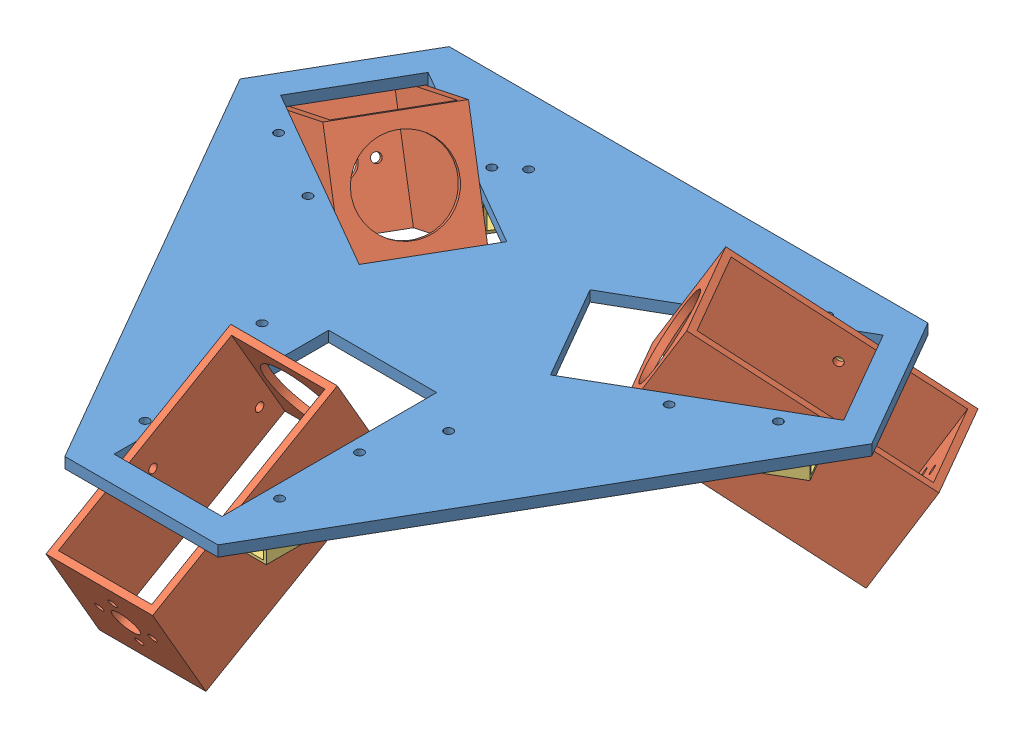
SolidWorks assembly 玉乗りロボット, configuration ﾃﾞﾌｫﾙﾄ. Lengths in mm.
Overall size (256.06 74.64 221.97).
10 component instances, 3 part files, 27 mates.
Components (placement in the parent):
- 土台1段目板-1: 土台1段目板 [ﾃﾞﾌｫﾙﾄ] at (77.4262 150.1357 151.9795) x (1 0 0) z (0 -1 0) size (237 205.25 4)
- モーター取り付け-1: モーター取り付け [ﾃﾞﾌｫﾙﾄ] at (156.673 133.6357 105.9377) x (0.75 -0.5 -0.433013) z (0.433013 0.866025 -0.25) size (80 40 40)
- モーター取り付け-2: モーター取り付け [ﾃﾞﾌｫﾙﾄ] at (-2.0705 133.6357 106.3707) x (-0.75 -0.5 -0.433013) z (-0.433013 0.866025 -0.25) size (80 40 40)
- モーター取り付け-3: モーター取り付け [ﾃﾞﾌｫﾙﾄ] at (77.6762 133.6357 243.6301) x (0 -0.5 0.866025) z (0 0.866025 0.5) size (80 40 40)
- 斜め取り付け角柱-1: 斜め取り付け角柱 [ﾃﾞﾌｫﾙﾄ] at (102.6762 141.1357 230.6397) size (10 10 50)
- 斜め取り付け角柱-2: 斜め取り付け角柱 [ﾃﾞﾌｫﾙﾄ] at (52.1762 141.1357 230.6397) size (10 10 50)
- 斜め取り付け角柱-3: 斜め取り付け角柱 [ﾃﾞﾌｫﾙﾄ] at (132.923 141.1357 90.7822) x (-0.5 0 -0.866025) z (0.866025 0 -0.5) size (10 10 50)
- 斜め取り付け角柱-4: 斜め取り付け角柱 [ﾃﾞﾌｫﾙﾄ] at (158.173 141.1357 134.5165) x (-0.5 0 -0.866025) z (0.866025 0 -0.5) size (10 10 50)
- 斜め取り付け角柱-5: 斜め取り付け角柱 [ﾃﾞﾌｫﾙﾄ] at (-3.3205 141.1357 134.5165) x (0.5 0 -0.866025) z (0.866025 0 0.5) size (10 10 50)
- 斜め取り付け角柱-6: 斜め取り付け角柱 [ﾃﾞﾌｫﾙﾄ] at (21.9295 141.1357 90.7822) x (0.5 0 -0.866025) z (0.866025 0 0.5) size (10 10 50)
Mates (geometry in assembly coordinates):
- 同心円1: concentric: circle of 土台1段目板-1; circle of 斜め取り付け角柱-1
- 同心円2: concentric: circle of 土台1段目板-1; circle of 斜め取り付け角柱-2
- 同心円3: concentric: circle of 土台1段目板-1; circle of 斜め取り付け角柱-3
- 同心円4: concentric: circle of 土台1段目板-1; circle of 斜め取り付け角柱-4
- 同心円5: concentric: circle of 土台1段目板-1; circle of 斜め取り付け角柱-6
- 同心円6: concentric: circle of 土台1段目板-1; circle of 斜め取り付け角柱-5
- 平行1: parallel: line of 土台1段目板-1 through (97.6762 150.1357 181.7295) axis (0 0 1); plane of 斜め取り付け角柱-1 through (97.6762 136.1357 255.6397) normal (-1 0 0)
- 平行2: parallel: line of 土台1段目板-1 through (57.1762 150.1357 262.2295) axis (0 0 -1); plane of 斜め取り付け角柱-2 through (57.1762 136.1357 255.6397) normal (1 0 0)
- 平行3: parallel: line of 土台1段目板-1 through (93.0655 146.1357 119.5675) axis (0.866025 0 -0.5); plane of 斜め取り付け角柱-3 through (157.0736 136.1357 82.6123) normal (0.5 0 0.866025)
- 平行4: parallel: line of 土台1段目板-1 through (183.0305 146.1357 114.3915) axis (-0.866025 0 0.5); plane of 斜め取り付け角柱-4 through (177.3236 136.1357 117.6864) normal (-0.5 0 -0.866025)
- 平行5: parallel: line of 土台1段目板-1 through (-7.9281 146.1357 79.3175) axis (0.866025 0 0.5); plane of 斜め取り付け角柱-6 through (41.0801 136.1357 107.6123) normal (-0.5 0 0.866025)
- 平行6: parallel: line of 土台1段目板-1 through (41.537 146.1357 154.6415) axis (-0.866025 0 -0.5); plane of 斜め取り付け角柱-5 through (20.8301 136.1357 142.6864) normal (0.5 0 -0.866025)
- 一致1: coincident: plane of 土台1段目板-1 through (77.4262 146.1357 151.9795) normal (0 -1 0); plane of 斜め取り付け角柱-1 through (97.6762 146.1357 255.6397) normal (0 1 0)
- 一致2: coincident: plane of 土台1段目板-1 through (77.4262 146.1357 151.9795) normal (0 -1 0); plane of 斜め取り付け角柱-2 through (47.1762 146.1357 255.6397) normal (0 1 0)
- 一致3: coincident: plane of 土台1段目板-1 through (77.4262 146.1357 151.9795) normal (0 -1 0); plane of 斜め取り付け角柱-4 through (182.3236 146.1357 126.3466) normal (0 1 0)
- 一致4: coincident: plane of 土台1段目板-1 through (77.4262 146.1357 151.9795) normal (0 -1 0); plane of 斜め取り付け角柱-3 through (157.0736 146.1357 82.6123) normal (0 1 0)
- 一致5: coincident: plane of 土台1段目板-1 through (77.4262 146.1357 151.9795) normal (0 -1 0); plane of 斜め取り付け角柱-6 through (41.0801 146.1357 107.6123) normal (0 1 0)
- 一致6: coincident: plane of 土台1段目板-1 through (77.4262 146.1357 151.9795) normal (0 -1 0); plane of 斜め取り付け角柱-5 through (15.8301 146.1357 151.3466) normal (0 1 0)
- 同心円7: concentric: circle of モーター取り付け-1; circle of 斜め取り付け角柱-4
- 同心円8: concentric: circle of モーター取り付け-1; circle of 斜め取り付け角柱-4
- 一致7: coincident: plane of モーター取り付け-1 through (125.3333 170.9562 100.9377) normal (-0.5 0 -0.866025); plane of 斜め取り付け角柱-3 through (157.0736 136.1357 82.6123) normal (0.5 0 0.866025)
- 同心円9: concentric: circle of モーター取り付け-3; circle of 斜め取り付け角柱-2
- 同心円10: concentric: circle of モーター取り付け-3; circle of 斜め取り付け角柱-2
- 一致8: coincident: plane of モーター取り付け-3 through (97.6762 170.9562 218.9891) normal (1 0 0); plane of 斜め取り付け角柱-1 through (97.6762 136.1357 255.6397) normal (-1 0 0)
- 同心円11: concentric: circle of モーター取り付け-2; circle of 斜め取り付け角柱-6
- 同心円12: concentric: circle of モーター取り付け-2; circle of 斜め取り付け角柱-6
- 一致9: coincident: plane of モーター取り付け-2 through (9.2692 170.9562 136.0117) normal (-0.5 0 0.866025); plane of 斜め取り付け角柱-5 through (20.8301 136.1357 142.6864) normal (0.5 0 -0.866025)
